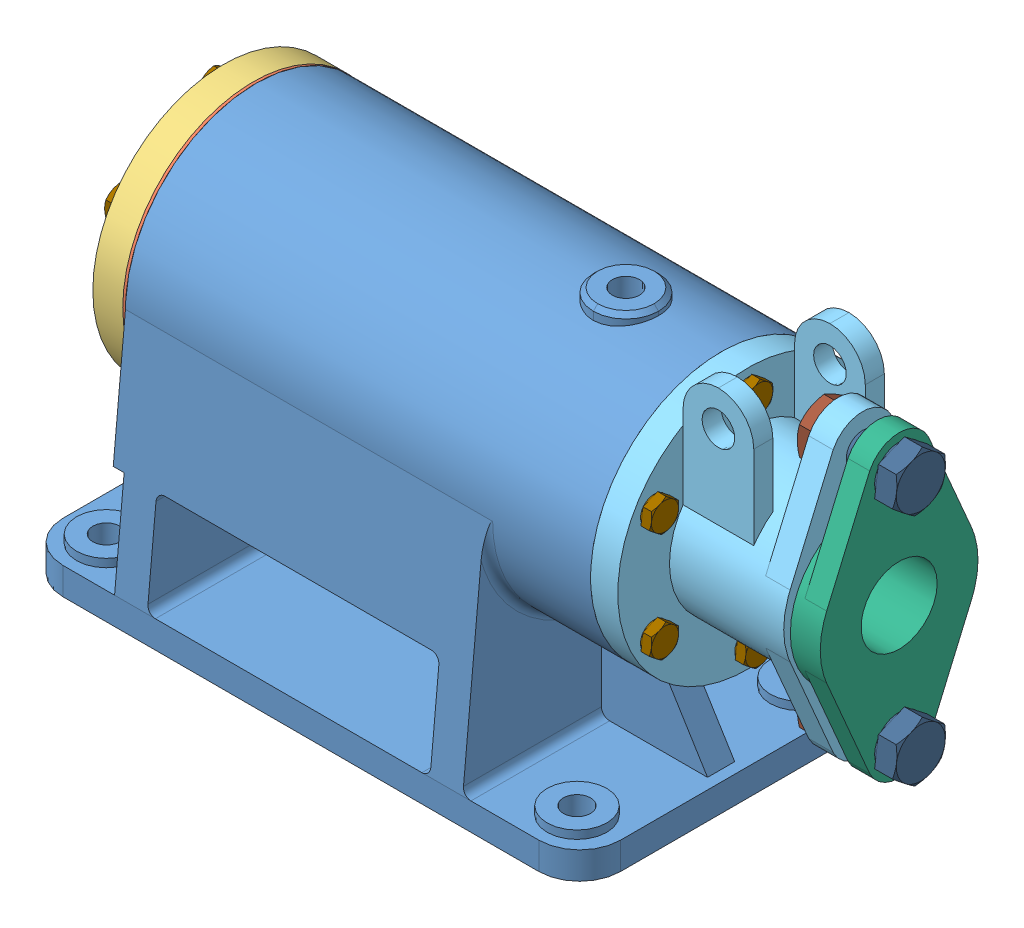
SolidWorks assembly Сборка корпуса - МЛИ2.01.00, configuration По умолчанию. Lengths in mm.
Overall size (274.39 155 112).
24 component instances, 11 part files, 52 mates.
Components (placement in the parent):
- Корпус - МЛИ2.00.01-1: Корпус - МЛИ2.00.01 [По умолчанию] at origin size (205 146 112)
- Прокладка - МЛИ2.00.07-1: Прокладка - МЛИ2.00.07 [По умолчанию] at (29 95 56) x (0 0 -1) z (1 0 0) size (96 96 1)
- Крышка - МЛИ2.00.02-3: Крышка - МЛИ2.00.02 [По умолчанию] at (18 95 56) x (0 0 -1) z (1 0 0) size (96 96 28)
- Кольцо уплотнительное-1: Кольцо уплотнительное [По умолчанию] at (35.9 95 56) x (-1 0 0) z (0 -0.955563 0.294787) size (5.8 65.6 65.6)
- Стакан - МЛИ2.00.06-1: Стакан - МЛИ2.00.06 [По умолчанию] at (211 95 56) x (0 0 1) z (-1 0 0) size (96 115 56)
- Фланец - МЛИ2.00.03-2: Фланец - МЛИ2.00.03 [По умолчанию] at (224.4398 95 56) x (0 0 -1) z (-1 0 0) size (58 110 44)
- Войлок-1: Войлок [По умолчанию] at (227.3473 95 56) x (-1 0 0) z (0 -0.960759 0.277384) size (27 45 45)
- Кольцо уплотнительное 1-1: Кольцо уплотнительное 1 [По умолчанию] at (182.9 95 56) size (5.8 33.8 33.8)
- hex screw gradeab_iso-2: hex screw gradeab_iso [ISO 4017 - M6 x 25-N] at (215 75 21.359) x (-1 0 0) z (0 0.924225 0.381849) size (29 11.55 10)
- hex screw gradeab_iso-3: hex screw gradeab_iso [ISO 4017 - M6 x 25-N] at (215 115 21.359) x (-1 0 0) z (0 0.924225 0.381849) size (29 11.55 10)
- hex screw gradeab_iso-4: hex screw gradeab_iso [ISO 4017 - M6 x 25-N] at (215 75 90.641) x (-1 0 0) z (0 0.924225 0.381849) size (29 11.55 10)
- hex screw gradeab_iso-5: hex screw gradeab_iso [ISO 4017 - M6 x 25-N] at (215 115 90.641) x (-1 0 0) z (0 0.924225 0.381849) size (29 11.55 10)
- hex screw gradeab_iso-6: hex screw gradeab_iso [ISO 4017 - M6 x 25-N] at (215 135 56) x (-1 0 0) z (0 0.924225 0.381849) size (29 11.55 10)
- hex screw gradeab_iso-7: hex screw gradeab_iso [ISO 4017 - M6 x 25-N] at (215 55 56) x (-1 0 0) z (0 0.924225 0.381849) size (29 11.55 10)
- hex screw gradeab_iso-14: hex screw gradeab_iso [ISO 4017 - M6 x 25-N] at (14 135 56) size (29 11.55 10)
- hex screw gradeab_iso-15: hex screw gradeab_iso [ISO 4017 - M6 x 25-N] at (14 115 90.641) size (29 11.55 10)
- hex screw gradeab_iso-16: hex screw gradeab_iso [ISO 4017 - M6 x 25-N] at (14 75 90.641) size (29 11.55 10)
- hex screw gradeab_iso-17: hex screw gradeab_iso [ISO 4017 - M6 x 25-N] at (14 55 56) size (29 11.55 10)
- hex screw gradeab_iso-18: hex screw gradeab_iso [ISO 4017 - M6 x 25-N] at (14 75 21.359) size (29 11.55 10)
- hex screw gradeab_iso-19: hex screw gradeab_iso [ISO 4017 - M6 x 25-N] at (14 115 21.359) size (29 11.55 10)
- hex screw gradec_iso-1: hex screw gradec_iso [ISO 4018 - M12 x 30-WN] at (274.3898 138 56) x (-1 0 0) z (0 0.924225 0.381849) size (37.95 20.78 18)
- hex screw gradec_iso-2: hex screw gradec_iso [ISO 4018 - M12 x 30-WN] at (274.3898 52 56) x (-1 0 0) z (0 0.924225 0.381849) size (37.95 20.78 18)
- hex thin nut chamfered gradeab_iso-3: hex thin nut chamfered gradeab_iso [ISO - 4035 - M12 - N] at (238 138 56) x (0 0 1) z (-1 0 0) size (18 20.78 6)
- hex thin nut chamfered gradeab_iso-4: hex thin nut chamfered gradeab_iso [ISO - 4035 - M12 - N] at (238 52 56) x (0 0 1) z (-1 0 0) size (18 20.78 6)
Mates (geometry in assembly coordinates):
- Совпадение1: coincident anti-aligned: plane of Корпус - МЛИ2.00.01-1 through (30 0 0) normal (-1 0 0); plane of Прокладка - МЛИ2.00.07-1 through (30 95 56) normal (1 0 0)
- Концентричный1: concentric aligned: cylinder of Корпус - МЛИ2.00.01-1 through (49 135 56) axis (-1 0 0) radius 3; cylinder of Прокладка - МЛИ2.00.07-1 through (30 135 56) axis (-1 0 0) radius 3.5
- Концентричный2: concentric aligned: cylinder of Корпус - МЛИ2.00.01-1 through (49 55 56) axis (-1 0 0) radius 3; cylinder of Прокладка - МЛИ2.00.07-1 through (30 55 56) axis (-1 0 0) radius 3.5
- Концентричный3: concentric anti-aligned: cylinder of Крышка - МЛИ2.00.02-3 through (46 95 56) axis (-1 0 0) radius 33; axis of Кольцо уплотнительное-1 through (17.3093 95 56) axis (1 0 0)
- Касательность3: tangent anti-aligned: plane of Крышка - МЛИ2.00.02-3 through (33 95 56) normal (1 0 0); torus of Кольцо уплотнительное-1
- Параллельность1: parallel anti-aligned: plane of Прокладка - МЛИ2.00.07-1 through (29 95 56) normal (-1 0 0); plane of Крышка - МЛИ2.00.02-3 through (29 95 56) normal (1 0 0)
- Концентричный8: concentric aligned: cylinder of Корпус - МЛИ2.00.01-1 through (49 135 56) axis (-1 0 0) radius 3; cylinder of Крышка - МЛИ2.00.02-3 through (29 135 56) axis (-1 0 0) radius 3
- Концентричный9: concentric aligned: cylinder of Корпус - МЛИ2.00.01-1 through (49 75 90.641) axis (-1 0 0) radius 3; cylinder of Крышка - МЛИ2.00.02-3 through (29 75 90.641) axis (-1 0 0) radius 3
- Граничное расстояние1: limit distance = 0 mm anti-aligned: plane of Крышка - МЛИ2.00.02-3 through (29 95 56) normal (1 0 0); plane of Прокладка - МЛИ2.00.07-1 through (29 95 56) normal (-1 0 0)
- Совпадение2: coincident anti-aligned: plane of Корпус - МЛИ2.00.01-1 through (201 0 0) normal (1 0 0); plane of Стакан - МЛИ2.00.06-1 through (201 95 56) normal (-1 0 0)
- Концентричный10: concentric anti-aligned: cylinder of Корпус - МЛИ2.00.01-1 through (182 75 21.359) axis (1 0 0) radius 3; cylinder of Стакан - МЛИ2.00.06-1 through (211 75 21.359) axis (-1 0 0) radius 3.5
- Концентричный11: concentric anti-aligned: cylinder of Корпус - МЛИ2.00.01-1 through (182 135 56) axis (1 0 0) radius 3; cylinder of Стакан - МЛИ2.00.06-1 through (211 135 56) axis (-1 0 0) radius 3.5
- Концентричный13: concentric aligned: cylinder of Стакан - МЛИ2.00.06-1 through (197 95 56) axis (1 0 0) radius 22.5; cylinder of Фланец - МЛИ2.00.03-2 through (222.4398 95 56) axis (1 0 0) radius 22.5
- Граничное расстояние3: limit distance = 2.4398 mm anti-aligned: plane of Фланец - МЛИ2.00.03-2 through (255.4398 95 56) normal (-1 0 0); plane of Стакан - МЛИ2.00.06-1 through (253 52 56) normal (1 0 0)
- Концентричный14: concentric aligned: cylinder of Стакан - МЛИ2.00.06-1 through (244 138 56) axis (1 0 0) radius 6; cylinder of Фланец - МЛИ2.00.03-2 through (257.4398 138 56) axis (1 0 0) radius 6
- Концентричный15: concentric aligned: cylinder of Стакан - МЛИ2.00.06-1 through (197 95 56) axis (1 0 0) radius 22.5; cylinder of Войлок-1 through (227.3473 95 56) axis (1 0 0) radius 22.5
- Совпадение6: coincident aligned: cone of Фланец - МЛИ2.00.03-2 through (227.3473 95 56) axis (1 0 0); cone of Войлок-1 through (227.3473 95 56) axis (1 0 0)
- Граничное расстояние4: limit distance = 5.3473 mm anti-aligned: plane of Войлок-1 through (200.3473 91.1166 42.5494) normal (-1 0 0); plane of Корпус - МЛИ2.00.01-1 through (195 95 56) normal (1 0 0)
- Совпадение8: coincident anti-aligned: line of Корпус - МЛИ2.00.01-1 through (165 95 56) axis (1 0 0); line of Кольцо уплотнительное 1-1 through (192.5302 95 56) axis (-1 0 0)
- Касательность5: tangent anti-aligned: plane of Корпус - МЛИ2.00.01-1 through (180 95 56) normal (1 0 0); torus of Кольцо уплотнительное 1-1
- Концентричный16: concentric anti-aligned: cylinder of Стакан - МЛИ2.00.06-1 through (211 75 21.359) axis (-1 0 0) radius 3.5; cylinder of hex screw gradeab_iso-2 through (215 75 21.359) axis (1 0 0) radius 5
- Совпадение9: coincident anti-aligned: plane of Стакан - МЛИ2.00.06-1 through (211 95 56) normal (1 0 0); plane of hex screw gradeab_iso-2 through (211 72.7954 26.695) normal (-1 0 0)
- Концентричный17: concentric anti-aligned: cylinder of Стакан - МЛИ2.00.06-1 through (211 115 21.359) axis (-1 0 0) radius 3.5; cylinder of hex screw gradeab_iso-3 through (215 115 21.359) axis (1 0 0) radius 5
- Совпадение10: coincident anti-aligned: plane of Стакан - МЛИ2.00.06-1 through (211 95 56) normal (1 0 0); plane of hex screw gradeab_iso-3 through (211 112.7954 26.695) normal (-1 0 0)
- Концентричный18: concentric anti-aligned: cylinder of Стакан - МЛИ2.00.06-1 through (211 75 90.641) axis (-1 0 0) radius 3.5; cylinder of hex screw gradeab_iso-4 through (215 75 90.641) axis (1 0 0) radius 5
- Совпадение11: coincident anti-aligned: plane of Стакан - МЛИ2.00.06-1 through (211 95 56) normal (1 0 0); plane of hex screw gradeab_iso-4 through (211 72.7954 95.977) normal (-1 0 0)
- Концентричный19: concentric anti-aligned: cylinder of Стакан - МЛИ2.00.06-1 through (211 115 90.641) axis (-1 0 0) radius 3.5; cylinder of hex screw gradeab_iso-5 through (215 115 90.641) axis (1 0 0) radius 5
- Совпадение12: coincident anti-aligned: plane of Стакан - МЛИ2.00.06-1 through (211 95 56) normal (1 0 0); plane of hex screw gradeab_iso-5 through (211 112.7954 95.977) normal (-1 0 0)
- Концентричный20: concentric anti-aligned: cylinder of Стакан - МЛИ2.00.06-1 through (211 135 56) axis (-1 0 0) radius 3.5; cylinder of hex screw gradeab_iso-6 through (215 135 56) axis (1 0 0) radius 5
- Совпадение13: coincident anti-aligned: plane of Стакан - МЛИ2.00.06-1 through (211 95 56) normal (1 0 0); plane of hex screw gradeab_iso-6 through (211 132.7954 61.336) normal (-1 0 0)
- Концентричный21: concentric anti-aligned: cylinder of Стакан - МЛИ2.00.06-1 through (211 55 56) axis (-1 0 0) radius 3.5; cylinder of hex screw gradeab_iso-7 through (215 55 56) axis (1 0 0) radius 5
- Совпадение14: coincident anti-aligned: plane of Стакан - МЛИ2.00.06-1 through (211 95 56) normal (1 0 0); plane of hex screw gradeab_iso-7 through (211 52.7954 61.336) normal (-1 0 0)
- Концентричный28: concentric aligned: cylinder of Крышка - МЛИ2.00.02-3 through (29 135 56) axis (-1 0 0) radius 3; cylinder of hex screw gradeab_iso-14 through (14 135 56) axis (-1 0 0) radius 5
- Совпадение20: coincident anti-aligned: plane of Крышка - МЛИ2.00.02-3 through (18 95 56) normal (-1 0 0); plane of hex screw gradeab_iso-14 through (18 140.7735 56) normal (1 0 0)
- Концентричный29: concentric aligned: cylinder of Крышка - МЛИ2.00.02-3 through (29 115 90.641) axis (-1 0 0) radius 3; cylinder of hex screw gradeab_iso-15 through (14 115 90.641) axis (-1 0 0) radius 5
- Совпадение21: coincident anti-aligned: plane of Крышка - МЛИ2.00.02-3 through (18 95 56) normal (-1 0 0); plane of hex screw gradeab_iso-15 through (18 120.7735 90.641) normal (1 0 0)
- Концентричный30: concentric aligned: cylinder of Крышка - МЛИ2.00.02-3 through (29 75 90.641) axis (-1 0 0) radius 3; cylinder of hex screw gradeab_iso-16 through (14 75 90.641) axis (-1 0 0) radius 5
- Совпадение22: coincident anti-aligned: plane of Крышка - МЛИ2.00.02-3 through (18 95 56) normal (-1 0 0); plane of hex screw gradeab_iso-16 through (18 80.7735 90.641) normal (1 0 0)
- Концентричный31: concentric aligned: cylinder of Крышка - МЛИ2.00.02-3 through (29 55 56) axis (-1 0 0) radius 3; cylinder of hex screw gradeab_iso-17 through (14 55 56) axis (-1 0 0) radius 5
- Совпадение23: coincident anti-aligned: plane of Крышка - МЛИ2.00.02-3 through (18 95 56) normal (-1 0 0); plane of hex screw gradeab_iso-17 through (18 60.7735 56) normal (1 0 0)
- Концентричный32: concentric aligned: cylinder of Крышка - МЛИ2.00.02-3 through (29 75 21.359) axis (-1 0 0) radius 3; cylinder of hex screw gradeab_iso-18 through (14 75 21.359) axis (-1 0 0) radius 5
- Совпадение24: coincident anti-aligned: plane of Крышка - МЛИ2.00.02-3 through (18 95 56) normal (-1 0 0); plane of hex screw gradeab_iso-18 through (18 80.7735 21.359) normal (1 0 0)
- Концентричный33: concentric aligned: cylinder of Крышка - МЛИ2.00.02-3 through (29 115 21.359) axis (-1 0 0) radius 3; cylinder of hex screw gradeab_iso-19 through (14 115 21.359) axis (-1 0 0) radius 5
- Совпадение25: coincident anti-aligned: plane of Крышка - МЛИ2.00.02-3 through (18 95 56) normal (-1 0 0); plane of hex screw gradeab_iso-19 through (18 120.7735 21.359) normal (1 0 0)
- Концентричный34: concentric aligned: cylinder of Фланец - МЛИ2.00.03-2 through (257.4398 138 56) axis (1 0 0) radius 6; cylinder of hex screw gradec_iso-1 through (274.3898 138 56) axis (1 0 0) radius 6
- Совпадение26: coincident anti-aligned: plane of Фланец - МЛИ2.00.03-2 through (266.4398 138 56) normal (1 0 0); plane of hex screw gradec_iso-1 through (266.4398 121.364 49.1267) normal (-1 0 0)
- Концентричный35: concentric anti-aligned: cylinder of Фланец - МЛИ2.00.03-2 through (266.4398 52 56) axis (-1 0 0) radius 12; cylinder of hex screw gradec_iso-2 through (274.3898 52 56) axis (1 0 0) radius 6
- Совпадение27: coincident anti-aligned: plane of Фланец - МЛИ2.00.03-2 through (266.4398 138 56) normal (1 0 0); plane of hex screw gradec_iso-2 through (266.4398 35.364 49.1267) normal (-1 0 0)
- Концентричный38: concentric anti-aligned: cylinder of hex screw gradec_iso-1 through (274.3898 138 56) axis (1 0 0) radius 6; cylinder of hex thin nut chamfered gradeab_iso-3 through (263.0375 138 56) axis (-1 0 0) radius 6
- Совпадение29: coincident anti-aligned: plane of Стакан - МЛИ2.00.06-1 through (244 52 56) normal (-1 0 0); plane of hex thin nut chamfered gradeab_iso-3 through (244 148.3923 56) normal (1 0 0)
- Концентричный39: concentric anti-aligned: cylinder of Стакан - МЛИ2.00.06-1 through (244 52 56) axis (1 0 0) radius 6; cylinder of hex thin nut chamfered gradeab_iso-4 through (263.0375 52 56) axis (-1 0 0) radius 6
- Совпадение30: coincident anti-aligned: plane of Стакан - МЛИ2.00.06-1 through (244 52 56) normal (-1 0 0); plane of hex thin nut chamfered gradeab_iso-4 through (244 62.3923 56) normal (1 0 0)
